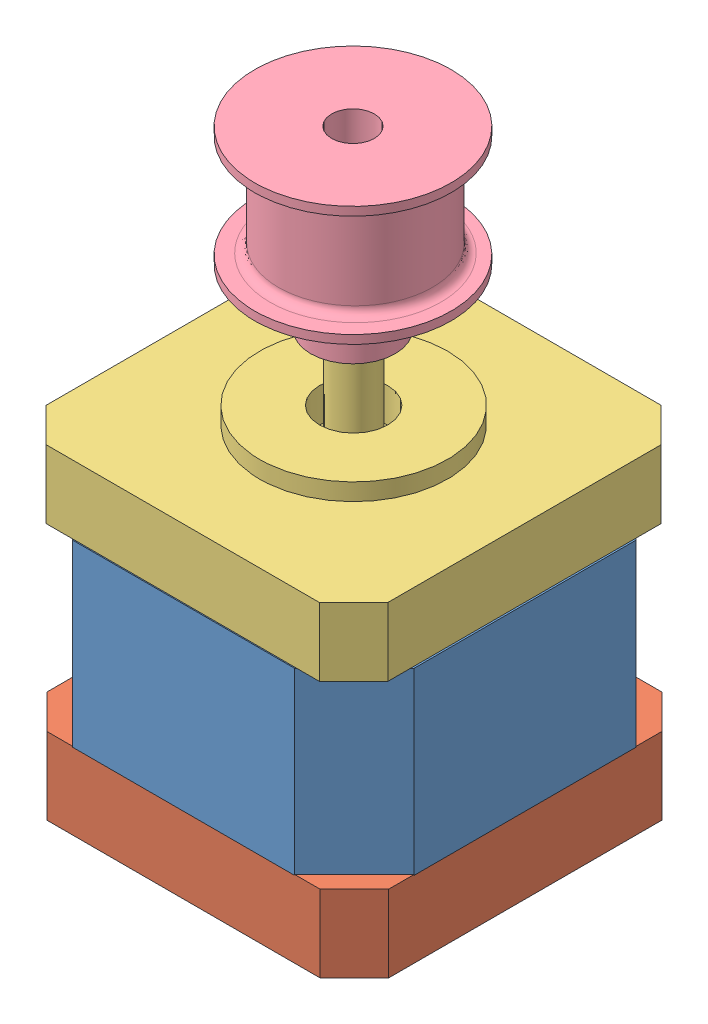
SolidWorks assembly motor_upper, configuration Default. Lengths in mm.
Overall size (42.09 68.31 42.01).
4 component instances, 4 part files, 0 mates.
Components (placement in the parent):
- middle-1: middle [Default] at (-5.5346 -7.2158 0.6893) size (42 21 42)
- bottom-1: bottom [Default] at (-5.5376 -16.1296 0.6793) size (42 9 42)
- upper-1: upper [Default] at (-5.6243 13.9005 0.6796) size (42 33 42)
- motor_gear-1: motor_gear [Default] at (-5.6782 31.5841 0.7046) size (23 20.6 23)
